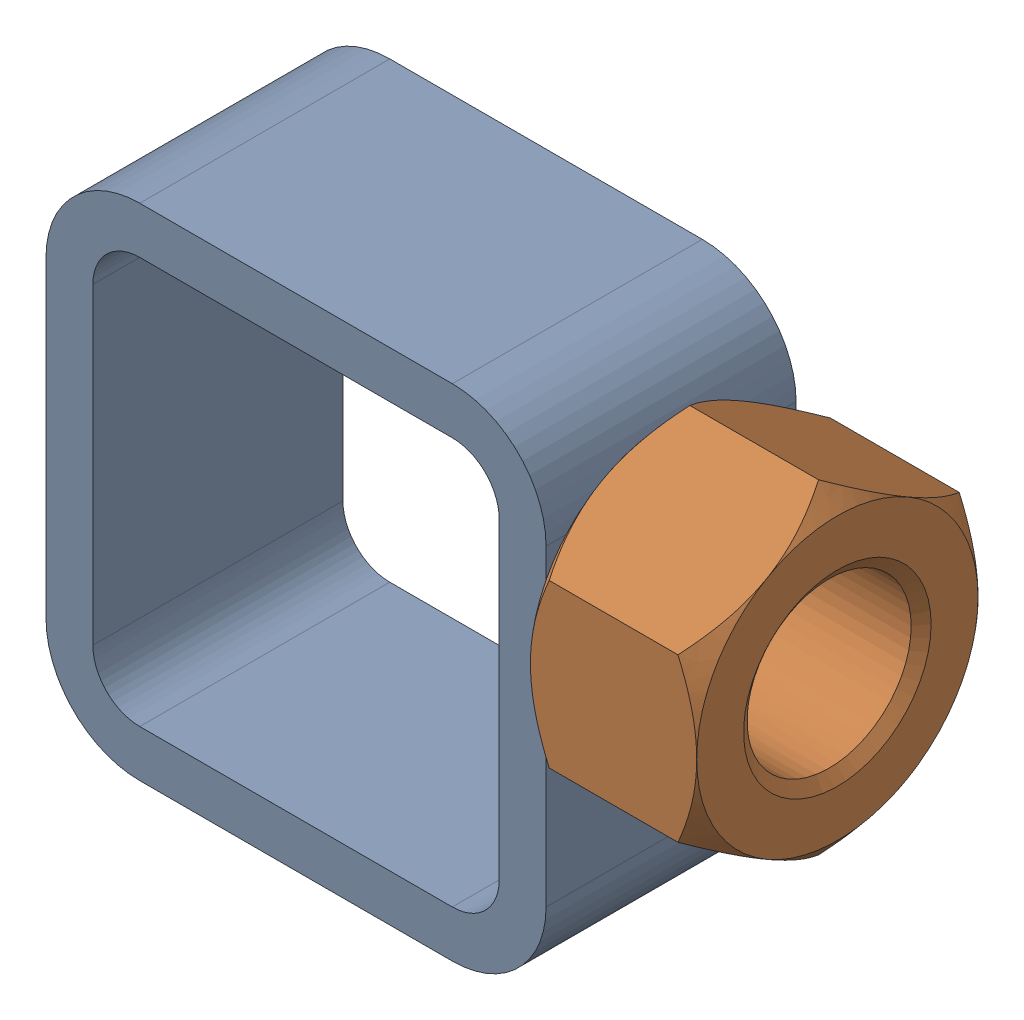
SolidWorks assembly 01-005-00-0-13, configuration Default. Lengths in mm.
Overall size (67.69 50.8 28.57).
2 component instances, 2 part files, 0 mates.
Components (placement in the parent):
- tube square_ai(PreviewCfg)-1: tube square_ai(PreviewCfg) [Default] at origin size (50.8 50.8 25.4)
- hex nut_ai(HNUT 0.7500-10-D-C)-1: hex nut_ai(HNUT 0.7500-10-D-C) [Default] at (67.691 31.75 0) x (0 0 -1) z (1 0 0) size (28.57 33 16.89)
